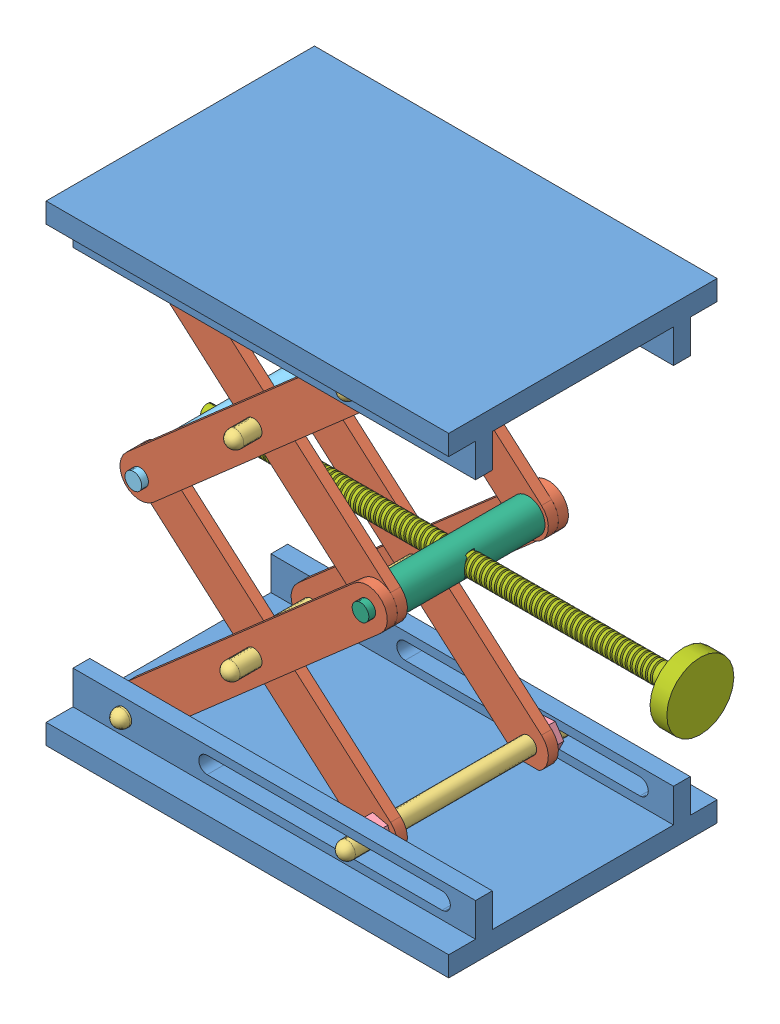
SolidWorks assembly 組合件1, configuration 預設. Lengths in mm.
Overall size (161 141.19 80).
23 component instances, 7 part files, 39 mates.
Components (placement in the parent):
- 上下平台-2: 上下平台 [預設] at (18.5092 8.6614 132.5718) x (1 0 0) z (0 0 -1) size (132 16.3 80)
- 交叉桿-2: 交叉桿 [預設] at (7.3622 43.3089 156.5718) x (0.752289 0.658833 0) z (0.658833 -0.752289 0) size (102 3 12)
- 交叉桿-4: 交叉桿 [預設] at (7.3622 43.3089 105.5718) x (0.752289 0.658833 0) z (0.658833 -0.752289 0) size (102 3 12)
- 支架-1: 支架 [預設] at (-26.4908 13.6614 136.1231) x (0 0 -1) z (-0.091861 0.995772 0) size (70 5 5)
- 交叉桿-5: 交叉桿 [預設] at (7.3622 43.3089 153.5718) x (0.752289 -0.658833 0) z (-0.658833 -0.752289 0) size (102 3 12)
- 交叉桿-6: 交叉桿 [預設] at (7.3622 43.3089 108.5718) x (0.752289 -0.658833 0) z (-0.658833 -0.752289 0) size (102 3 12)
- 墊片-1: 墊片 [預設] at (41.2152 13.6614 156.5718) x (-0.958982 0.283466 0) z (0 0 1) size (9.22 8.27 3)
- 墊片-2: 墊片 [預設] at (41.2152 13.6614 105.5718) x (1 0.000091 0) z (0 0 1) size (9.22 8.27 3)
- 支架-2: 支架 [預設] at (41.2152 13.6614 136.593) x (0 0 -1) z (0.712983 -0.701181 0) size (70 5 5)
- 支架-3: 支架 [預設] at (7.3622 43.3089 137.1225) x (0 0 -1) z (-0.599405 0.800446 0) size (70 5 5)
- 交叉桿-9: 交叉桿 [預設] at (7.3622 102.6038 105.5718) x (-0.752289 -0.658833 0) z (-0.658833 0.752289 0) size (102 3 12)
- 交叉桿-10: 交叉桿 [預設] at (7.3622 102.6038 108.5718) x (0.752289 -0.658833 0) z (-0.658833 -0.752289 0) size (102 3 12)
- 交叉桿-11: 交叉桿 [預設] at (7.3622 102.6038 156.5718) x (0.752289 0.658833 0) z (0.658833 -0.752289 0) size (102 3 12)
- 交叉桿-12: 交叉桿 [預設] at (7.3622 102.6038 153.5718) x (0.752289 -0.658833 0) z (-0.658833 -0.752289 0) size (102 3 12)
- 支架-4: 支架 [預設] at (7.3622 102.6038 136.0052) x (0 0 -1) z (0.806635 -0.59105 0) size (70 5 5)
- 中間支架-1: 中間支架 [預設] at (-26.4908 72.9563 132.5718) x (0 0 -1) z (1 0 0) size (58 10 10)
- 中間支架有螺紋-1: 中間支架有螺紋 [預設] at (41.2152 72.9563 132.5718) x (0 0 -1) z (-1 0 0) size (58 10 15)
- 螺旋桿-1: 螺旋桿 [預設] at (-18.7446 72.9563 132.5718) x (1 0 0) z (0 0.999771 -0.021395) size (147 20 20)
- 墊片-3: 墊片 [預設] at (-26.4908 132.2513 156.5718) size (9.22 8.27 3)
- 墊片-4: 墊片 [預設] at (-26.4908 132.2513 105.5718) x (0.896136 0.443779 0) z (0 0 1) size (9.22 8.27 3)
- 支架-5: 支架 [預設] at (41.2152 132.2513 136.405) x (0 0 -1) z (0.954104 -0.299476 0) size (70 5 5)
- 支架-6: 支架 [預設] at (-26.4908 132.2513 134.0803) x (0 0 -1) z (0.514901 -0.857249 0) size (70 5 5)
- 上下平台-3: 上下平台 [預設] at (18.5092 137.2513 132.5718) size (132 16.3 80)
Mates (geometry in assembly coordinates):
- 重合/共線/共點1: coincident anti-aligned: circle of 上下平台-2; circle of 交叉桿-2
- 重合/共線/共點3: coincident anti-aligned: circle of 上下平台-2; circle of 交叉桿-4
- 同軸心1: concentric aligned: cylinder of 交叉桿-4 through (-26.4908 13.6614 105.5708) axis (0 0 1) radius 2.5; cylinder of 支架-1 through (-26.4908 13.6614 165.1231) axis (0 0 1) radius 2.5
- 重合/共線/共點4: coincident anti-aligned: circle of 交叉桿-2; circle of 交叉桿-5
- 重合/共線/共點5: coincident anti-aligned: circle of 交叉桿-4; circle of 交叉桿-6
- 重合/共線/共點6: coincident anti-aligned: circle of 交叉桿-5; circle of 墊片-1
- 相切(T)1: tangent anti-aligned: plane of 上下平台-2 through (-1.4908 11.1614 92.5708) normal (0 1 0); cylinder of 墊片-1 through (41.2152 13.6614 156.5708) axis (0 0 1) radius 2.5
- 重合/共線/共點11: coincident anti-aligned: circle of 交叉桿-6; circle of 墊片-2
- 相切(T)3: tangent anti-aligned: plane of 上下平台-2 through (-1.4908 11.1614 172.5728) normal (0 1 0); cylinder of 墊片-2 through (41.2152 13.6614 105.5708) axis (0 0 1) radius 2.5
- 同軸心5: concentric aligned: cylinder of 交叉桿-5 through (41.2152 13.6614 153.5708) axis (0 0 1) radius 2.5; cylinder of 交叉桿-6 through (41.2152 13.6614 108.5708) axis (0 0 1) radius 2.5
- 同軸心6: concentric aligned: cylinder of 交叉桿-5 through (41.2152 13.6614 153.5708) axis (0 0 1) radius 2.5; cylinder of 支架-2 through (41.2152 13.6614 165.593) axis (0 0 1) radius 2.5
- 同軸心7: concentric aligned: cylinder of 交叉桿-2 through (7.3622 43.3089 156.5708) axis (0 0 1) radius 2.5; cylinder of 支架-3 through (7.3622 43.3089 166.1225) axis (0 0 1) radius 2.5
- 重合/共線/共點17: coincident anti-aligned: circle of 交叉桿-6; circle of 交叉桿-9
- 重合/共線/共點19: coincident anti-aligned: circle of 交叉桿-4; circle of 交叉桿-10
- 同軸心9: concentric aligned: cylinder of 交叉桿-9 through (7.3622 102.6038 105.5708) axis (0 0 1) radius 2.5; cylinder of 交叉桿-10 through (7.3622 102.6038 108.5708) axis (0 0 1) radius 2.5
- 重合/共線/共點20: coincident anti-aligned: circle of 交叉桿-5; circle of 交叉桿-11
- 重合/共線/共點21: coincident anti-aligned: circle of 交叉桿-2; circle of 交叉桿-12
- 同軸心10: concentric aligned: cylinder of 交叉桿-11 through (7.3622 102.6038 156.5708) axis (0 0 1) radius 2.5; cylinder of 交叉桿-12 through (7.3622 102.6038 153.5708) axis (0 0 1) radius 2.5
- 同軸心12: concentric aligned: cylinder of 交叉桿-10 through (7.3622 102.6038 108.5708) axis (0 0 1) radius 2.5; cylinder of 支架-4 through (7.3622 102.6038 165.0052) axis (0 0 1) radius 2.5
- 同軸心13: concentric anti-aligned: cylinder of 交叉桿-5 through (-26.4908 72.9563 153.5708) axis (0 0 1) radius 2.5; cylinder of 中間支架-1 through (-26.4908 72.9563 103.5718) axis (0 0 -1) radius 2.5
- 重合/共線/共點23: coincident anti-aligned: plane of 交叉桿-5 through (-26.4908 72.9563 153.5718) normal (0 0 -1); plane of 中間支架-1 through (-26.4908 75.4563 153.5718) normal (0 0 1)
- 同軸心14: concentric anti-aligned: cylinder of 交叉桿-12 through (41.2152 72.9563 153.5708) axis (0 0 1) radius 2.5; cylinder of 中間支架有螺紋-1 through (41.2152 72.9563 103.5718) axis (0 0 -1) radius 2.5
- 重合/共線/共點24: coincident anti-aligned: plane of 交叉桿-10 through (-26.4908 132.2513 111.5718) normal (0 0 1); plane of 中間支架有螺紋-1 through (41.2152 67.9563 111.5718) normal (0 0 -1)
- 同軸心16: concentric aligned: cylinder of 中間支架-1 through (-36.4908 72.9563 132.5718) axis (1 0 0) radius 2; cylinder of 螺旋桿-1 through (113.5092 72.9563 132.5718) axis (1 0 0) radius 2
- 相切(T)5: tangent anti-aligned: cylinder of 中間支架-1 through (-26.4908 72.9563 103.5718) axis (0 0 -1) radius 5; plane of 螺旋桿-1 through (-21.4908 72.9136 130.5723) normal (-1 0 0)
- 相切(T)8: tangent: curve of 中間支架有螺紋-1; curve of 螺旋桿-1
- 重合/共線/共點25: coincident anti-aligned: circle of 交叉桿-12; circle of 墊片-3
- 重合/共線/共點26: coincident anti-aligned: circle of 交叉桿-10; circle of 墊片-4
- 垂直2: perpendicular: line of 上下平台-2 through (78.5092 8.6614 105.5718) axis (0 0 1); line of 上下平台-3 through (78.5092 127.2513 159.5718) axis (0 1 0)
- 平行(R)4: parallel anti-aligned: plane of 上下平台-2 through (18.5092 18.6614 132.5718) normal (0 1 0); plane of 上下平台-3 through (18.5092 127.2513 132.5718) normal (0 -1 0)
- 同軸心17: concentric aligned: cylinder of 墊片-3 through (-26.4908 132.2513 156.5708) axis (0 0 1) radius 2.5; cylinder of 支架-6 through (-26.4908 132.2513 163.0803) axis (0 0 1) radius 2.5
- 同軸心18: concentric aligned: cylinder of 交叉桿-11 through (41.2152 132.2513 156.5708) axis (0 0 1) radius 2.5; cylinder of 支架-5 through (41.2152 132.2513 165.405) axis (0 0 1) radius 2.5
- 平行(R)5: parallel anti-aligned: plane of 上下平台-2 through (18.5092 18.6614 132.5718) normal (0 1 0); plane of 上下平台-3 through (18.5092 127.2513 132.5718) normal (0 -1 0)
- 平行(R)7: parallel aligned: plane of 上下平台-2 through (-41.4908 18.6614 105.5718) normal (0 0 1); plane of 上下平台-3 through (-41.4908 127.2513 105.5718) normal (0 0 1)
- 平行(R)8: parallel anti-aligned: plane of 上下平台-2 through (18.5092 18.6614 132.5718) normal (0 1 0); plane of 上下平台-3 through (18.5092 127.2513 132.5718) normal (0 -1 0)
- 平行(R)10: parallel aligned: plane of 上下平台-2 through (-41.4908 18.6614 159.5718) normal (0 0 -1); plane of 上下平台-3 through (-41.4908 127.2513 159.5718) normal (0 0 -1)
- 平行(R)11: parallel aligned: plane of 上下平台-2 through (78.5092 2.6614 92.5718) normal (1 0 0); plane of 上下平台-3 through (78.5092 143.2513 172.5718) normal (1 0 0)
- 重合/共線/共點42: coincident anti-aligned: plane of 交叉桿-9 through (41.2152 132.2513 105.5718) normal (0 0 -1); plane of 上下平台-3 through (-41.4908 127.2513 105.5718) normal (0 0 1)
- 同軸心20: concentric anti-aligned: cylinder of 支架-6 through (-26.4908 132.2513 163.0803) axis (0 0 1) radius 2.5; cylinder of 上下平台-3 through (-26.4908 132.2513 172.5728) axis (0 0 -1) radius 2.5
